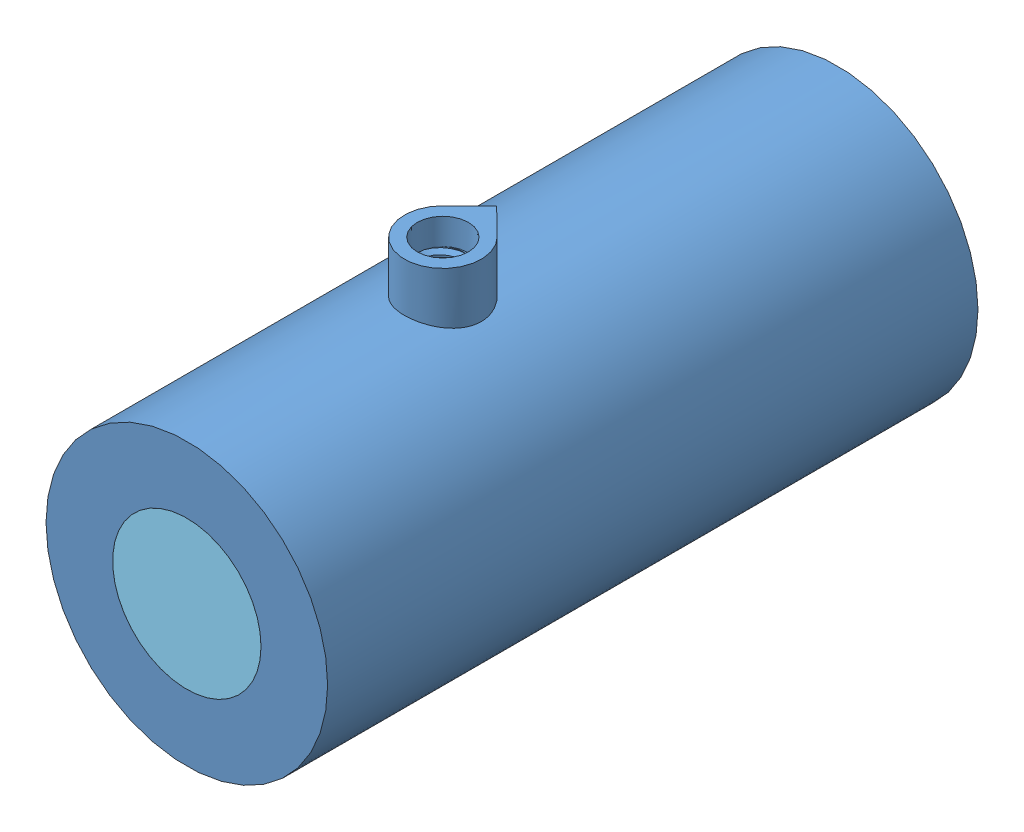
SolidWorks assembly globe_valve_005, configuration Default. Lengths in mm.
Overall size (22 25.8 50.81).
5 component instances, 5 part files, 3 mates.
Components (placement in the parent):
- globe_valve_test-005-1: globe_valve_test-005 [Default] at (24.4644 27.9344 35.1224) size (22 25.8 50.8)
- globe_valve_test-005_stopper-001-1: globe_valve_test-005_stopper-001 [Default] at (24.4644 35.3344 65.9224) x (0.608477 0 0.793571) z (-0.793571 0 0.608477) size (8.2 6.99 8.2)
- LID4-1: LID4 [Default] at origin size (4 0.31 4)
- LID5-1: LID5 [Default] at origin size (11.86 11.86 0.32)
- LID6-1: LID6 [Default] at origin size (11.86 11.86 0.32)
Mates (geometry in assembly coordinates):
- Concentric1: concentric: cone of globe_valve_test-005-1 through (24.4644 53.7344 65.9224) axis (0 -1 0); cylinder of globe_valve_test-005_stopper-001-1 through (24.4644 38.9344 65.9224) axis (0 1 0) radius 2
- Concentric2: concentric: cylinder of globe_valve_test-005-1 through (24.4644 36.7344 65.9224) axis (0 -1 0) radius 2.1; cylinder of globe_valve_test-005_stopper-001-1 through (24.4644 35.3344 65.9224) axis (0 -1 0) radius 2.1
- Width1: width = 1.4 mm: plane of globe_valve_test-005-1 through (66.7709 37.9344 71.7224) normal (0 1 0); plane of globe_valve_test-005-1 through (24.4644 42.3344 65.9224) normal (0 -1 0); plane of globe_valve_test-005_stopper-001-1 through (26.9244 39.3344 64.0361) normal (0 -1 0); plane of globe_valve_test-005_stopper-001-1 through (27.718 42.1344 63.4276) normal (0 1 0)
